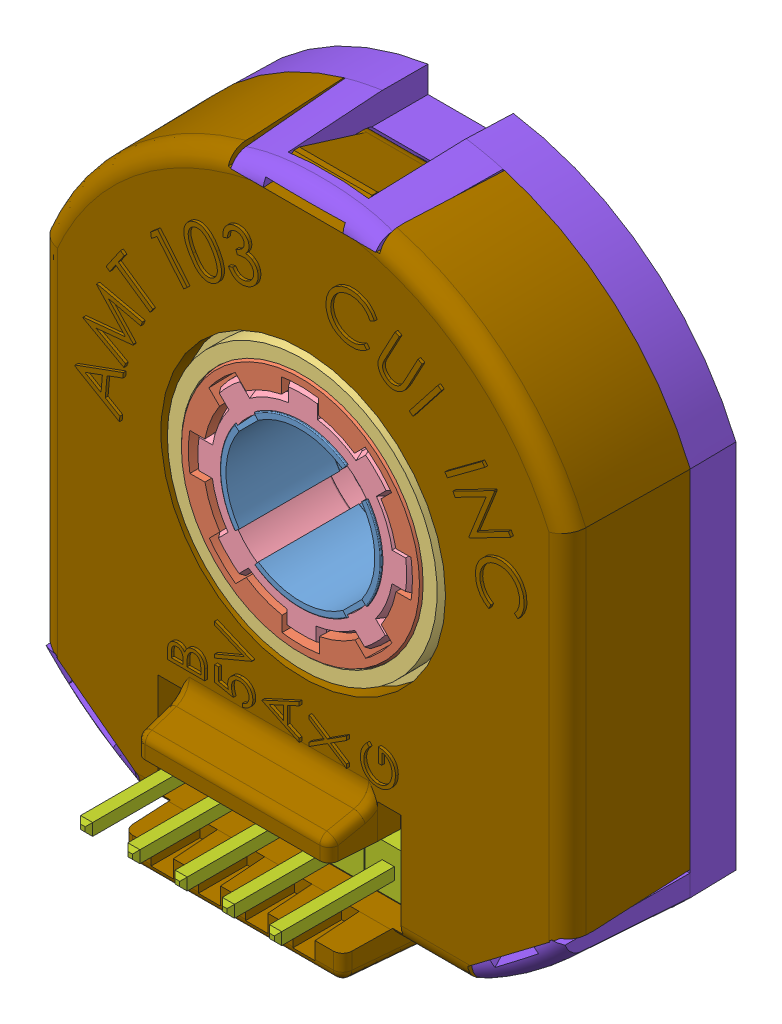
SolidWorks assembly CUI_cui_amt103-0048-n8000-s, configuration Default. Lengths in mm.
Overall size (36.33 37.04 14.49).
9 component instances, 9 part files, 0 mates.
Components (placement in the parent):
- CUI_amt-sleeve-rev-d(8 mm)-1: CUI_amt-sleeve-rev-d(8 mm) [Default] at (0 0 -2.42) x (0.999996 0.002864 0) z (0 0 1) size (10.79 10.79 7.8)
- CUI_amt-hub-top-rev-d1-1: CUI_amt-hub-top-rev-d1 [Default] at (0 0 2.13) x (0.999996 0.002864 0) z (0 0 1) size (14 14 5.67)
- CUI_amt-hub-bottom-rev-b-1: CUI_amt-hub-bottom-rev-b [Default] at (0 0 2.43) x (0.999998 -0.001942 0) z (0 0 1) size (17.3 17.3 3.2)
- CUI_amt10x-shaft-adaptor-rev-e-1: CUI_amt10x-shaft-adaptor-rev-e [Default] at (0 0 0.03) x (0.999996 0.002864 0) z (0 0 1) size (11.8 11.8 7.8)
- CUI_receiver-board-1: CUI_receiver-board [Default] at (72.2834 -20.351 3.03) x (-1 0 0) z (0 0 -1) size (26.5 26.62 0.41)
- CUI_rotor-board-rev f-1: CUI_rotor-board-rev f [Default] at (0 0 2.13) x (0.807874 -0.589355 0) z (0 0 1) size (26 26 0.3)
- CUI_transmitter-board amt10(amt-103)-1: CUI_transmitter-board amt10(amt-103) [Default] at (19.1596 -17.1102 1.22) x (-1 0 0) z (0 0 -1) size (26.63 29.61 12.1)
- CUI_amt-103-base-rev-k(default)-1: CUI_amt-103-base-rev-k(default) [Default] at (0 0 -1) x (-1 0 0) z (0 0 -1) size (28.59 34.62 9.11)
- CUI_amt-103-top-cover-rev-h-1: CUI_amt-103-top-cover-rev-h [Default] at (0 0 5.23) x (-1 0 0) z (0 0 -1) size (28.6 33.94 9.26)
